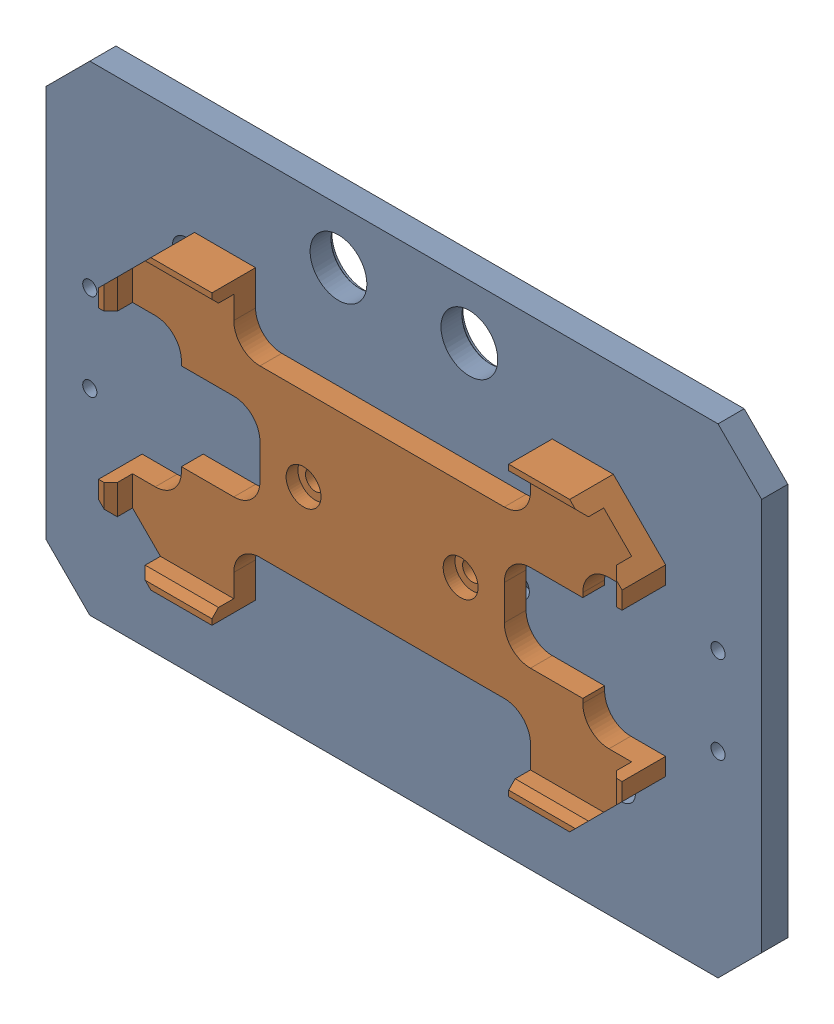
SolidWorks assembly 014-102A_PALETTE_KOMPLETT, configuration Default. Lengths in mm.
Overall size (164 110 16).
9 component instances, 5 part files, 0 mates.
Components (placement in the parent):
- 014-102a_Palette 110x164mm-1: 014-102a_Palette 110x164mm [Default] at origin size (164 110 6)
- 071-903_Aufnahmevorrichtung-1: 071-903_Aufnahmevorrichtung [Default] at (0 0 6) x (-1 0 0) z (0 0 1) size (120 66 10)
- ISO 7380 - M4 x 8-1: ISO 7380 - M4 x 8 [Default] at (18 0 8.3) x (0 0 -1) z (0.009675 0.999953 0) (suppressed, hidden)
- ISO 7380 - M4 x 8-2: ISO 7380 - M4 x 8 [Default] at (-18 0 8.3) x (0 0 -1) z (0.00137 0.999999 0) (suppressed, hidden)
- 014-105a_iCIM-Aufnahmebolzen-1: 014-105a_iCIM-Aufnahmebolzen [Default] at (-15 42.5 0.2) x (1 -0.000438 0) z (0 0 1) (suppressed, hidden)
- 014-105a_iCIM-Aufnahmebolzen-2: 014-105a_iCIM-Aufnahmebolzen [Default] at (15 42.5 0.2) (suppressed, hidden)
- _WERKST_X2_00FC_X0_CK-RAISONANCE-KOMPLETT_1-1: _WERKST_X2_00FC_X0_CK-RAISONANCE-KOMPLETT_1 [Default] at (-57 30 31) x (1 0 0) z (0 0 -1) (suppressed, hidden)
- _Reflektorfolie-1: _Reflektorfolie [Default] at (-62 51 6) (suppressed, hidden)
- _Reflektorfolie-2: _Reflektorfolie [Default] at (62 -51 6) (suppressed, hidden)
